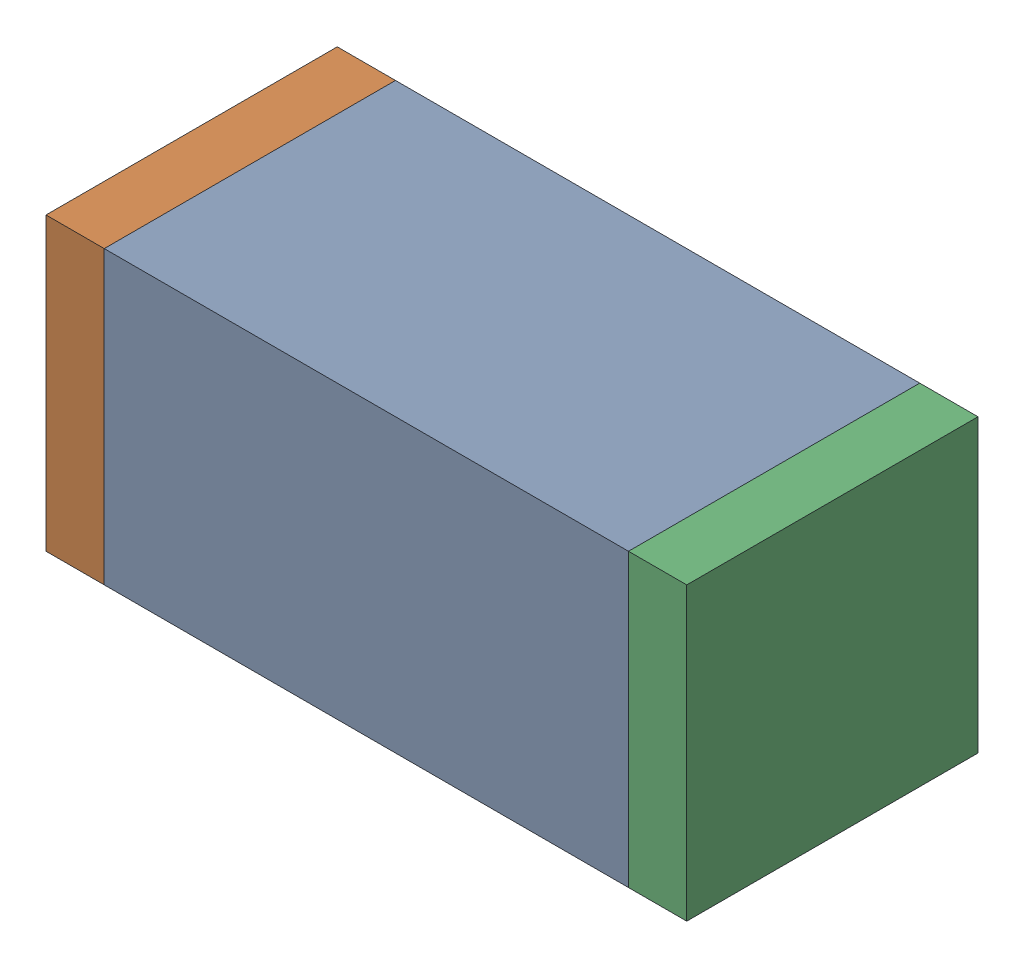
SolidWorks assembly C54, configuration Default. Lengths in mm.
Overall size (1.1 0.5 0.5).
6 component instances, 2 part files, 0 mates.
Components (placement in the parent):
- 836749680-1: 836749680 [Default] at (107 45.2 0) size (0.9 0.5 0.5)
  - Extruded_4-1: Extruded_4 [Default] at origin size (0.9 0.5 0.5)
- 810156080-1: 810156080 [Default] at (106.5 45.2 0) size (0.1 0.5 0.5)
  - Extruded_5-1: Extruded_5 [Default] at origin size (0.1 0.5 0.5)
- 810156080-2: 810156080 [Default] at (107.5 45.2 0) size (0.1 0.5 0.5)
  - Extruded_5-1: Extruded_5 [Default] at origin size (0.1 0.5 0.5)
